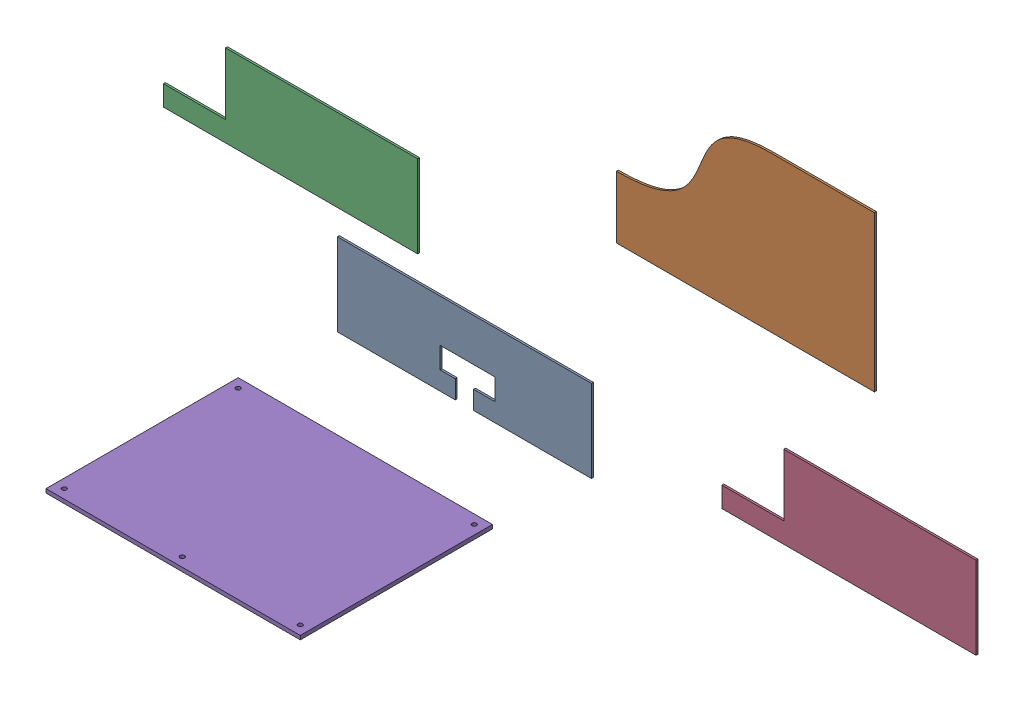
SolidWorks assembly Package Space, configuration Default. Lengths in mm.
Overall size (1111.83 499.31 578.99).
5 component instances, 4 part files, 0 mates.
Components (placement in the parent):
- FrontWall-1: FrontWall [Default] at (216.1129 24.7252 79.636) size (416.08 134.78 3.17)
- BackWall-1: BackWall [Default] at (294.3374 113.3385 -203.016) size (422.43 254 3.17)
- LeftWall-1: LeftWall [Default] at (-330.9683 181.1034 59.8327) size (416.08 134.78 3.17)
- LeftWall-2: LeftWall [Default] at (364.7771 -148.8111 -158.0621) size (416.08 134.78 3.17)
- PackageBase-1: PackageBase [Default] at (-89.6667 -172.6309 74.3491) size (416.08 6.35 314.48)
